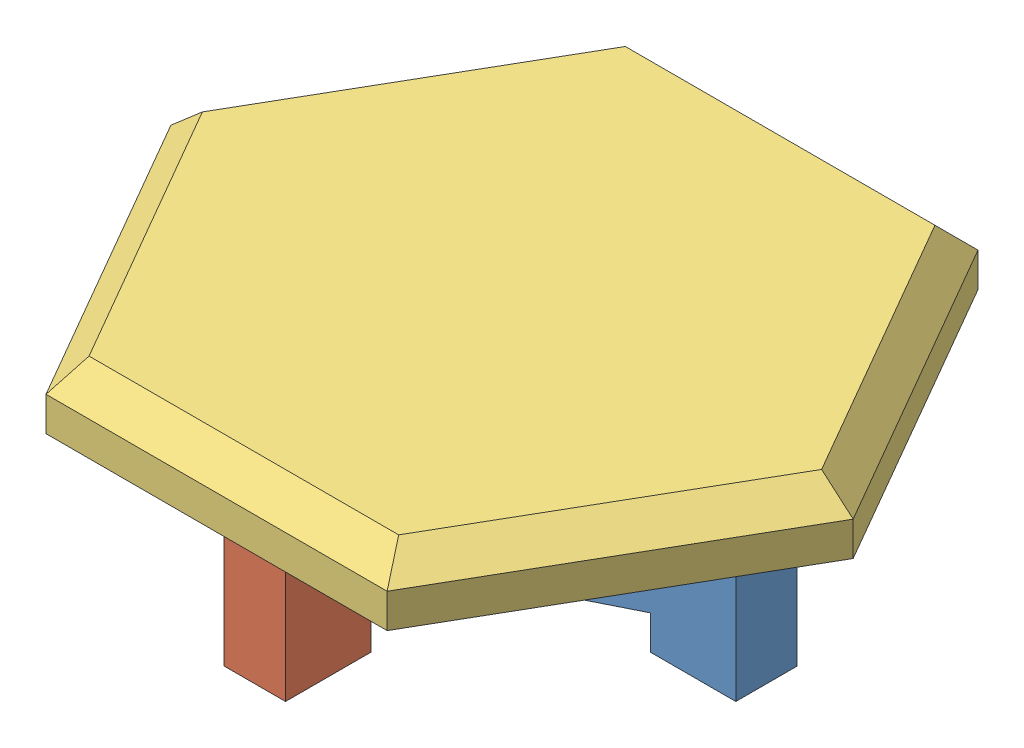
SolidWorks assembly Small Teapot Assembly Explode, configuration Default. Lengths in mm.
Overall size (200 62 173.21).
3 component instances, 3 part files, 5 mates.
Components (placement in the parent):
- Base 1-1: Base 1 [Default] at (-2.4513 11.9193 -15.8042) size (150 44 18)
- Base2-1: Base2 [Default] at (-11.4513 11.9193 -6.8042) x (0 0 -1) z (1 0 0) size (150 44 18)
- Teapot Top-1: Teapot Top [Default] at (-2.5549 33.9193 -7.2964) size (200 18 173.21)
Mates (geometry in assembly coordinates):
- Coincident1: coincident anti-aligned: plane of Base 1-1 through (-11.4513 11.9193 -15.8042) normal (0 1 0); plane of Base2-1 through (-11.4513 11.9193 2.1958) normal (0 -1 0)
- Coincident2: coincident anti-aligned: plane of Base 1-1 through (-77.4513 33.9193 2.1958) normal (0 0 1); plane of Base2-1 through (-11.4513 11.9193 2.1958) normal (0 0 -1)
- Coincident4: coincident aligned: plane of Base 1-1 through (72.5487 33.9193 2.1958) normal (0 1 0); plane of Base2-1 through (6.5487 33.9193 -81.8042) normal (0 1 0)
- Coincident5: coincident aligned: line of Base 1-1 through (6.5487 33.9193 -15.8042) axis (0 0 1); line of Base2-1 through (6.5487 33.9193 -81.8042) axis (0 0 1)
- Coincident6: coincident anti-aligned: plane of Base2-1 through (6.5487 33.9193 -81.8042) normal (0 1 0); plane of Teapot Top-1 through (97.4451 33.9193 -7.2964) normal (0 -1 0)
